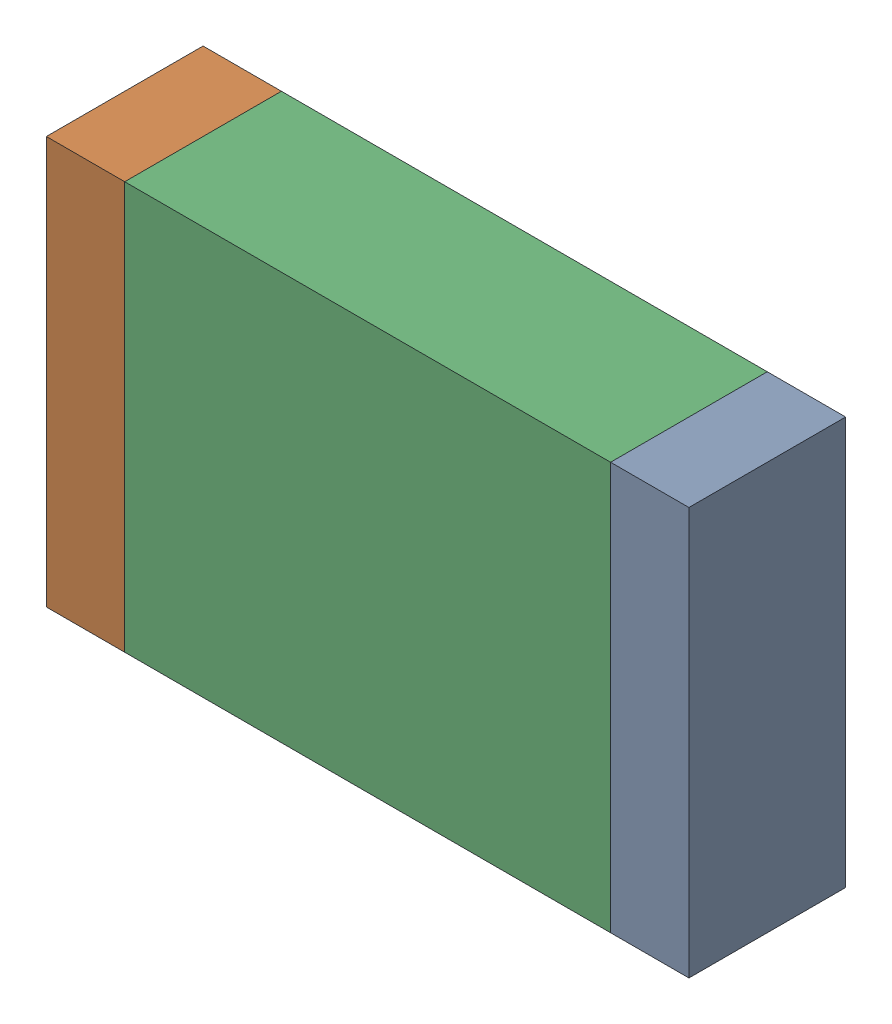
SolidWorks assembly C88, configuration Default. Lengths in mm.
Overall size (2.05 1.3 0.5).
6 component instances, 2 part files, 0 mates.
Components (placement in the parent):
- 836756336-1: 836756336 [Default] at (108.875 65.5 0) size (0.25 1.3 0.5)
  - Extruded_41-1: Extruded_41 [Default] at origin size (0.25 1.3 0.5)
- 836756336-2: 836756336 [Default] at (107.075 65.5 0) size (0.25 1.3 0.5)
  - Extruded_41-1: Extruded_41 [Default] at origin size (0.25 1.3 0.5)
- 836756464-1: 836756464 [Default] at (107.975 65.5 0) size (1.55 1.3 0.5)
  - Extruded_42-1: Extruded_42 [Default] at origin size (1.55 1.3 0.5)
